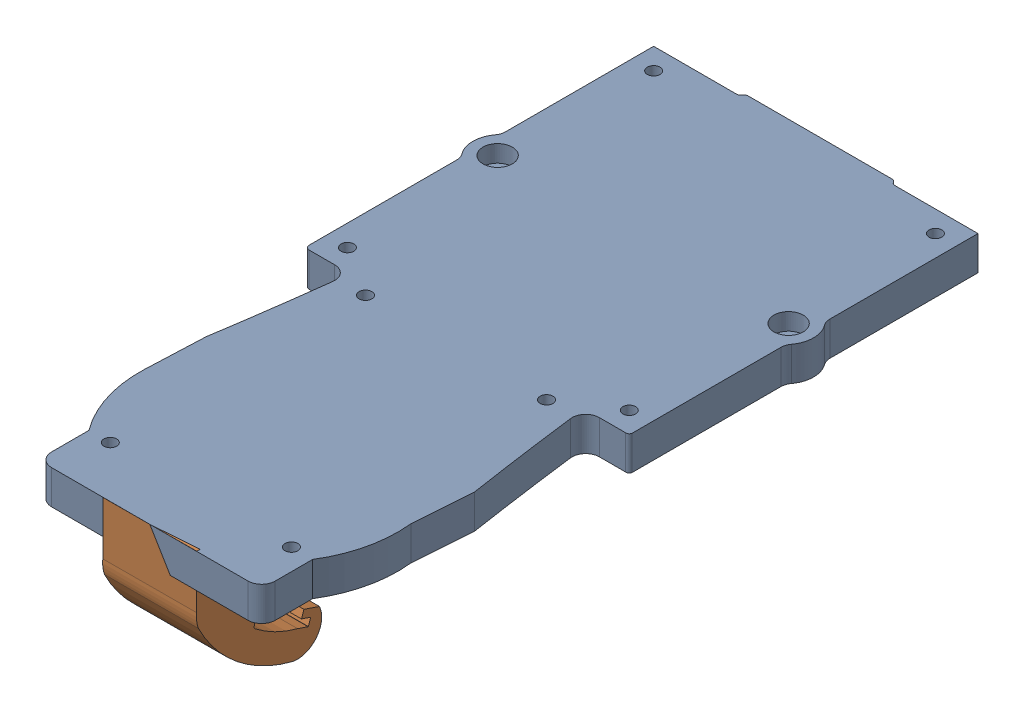
SolidWorks assembly Assem1, configuration Default. Lengths in mm.
Overall size (63.56 30.41 131.47).
2 component instances, 2 part files, 1 mates.
Components (placement in the parent):
- top drone-1: top drone [Default] at (-44.1909 -1.983 61.2759) size (63.56 6.35 125.08)
- hook on top-1: hook on top [Default] at (-25.9568 2.2668 63.2888) x (-0.002781 -0.323272 -0.946302) z (0.999996 0.000123 -0.002981) size (29.61 22.02 17.46)
Mates (geometry in assembly coordinates):
- Coincident4: coincident: point of top drone-1; unknown of hook on top-1
